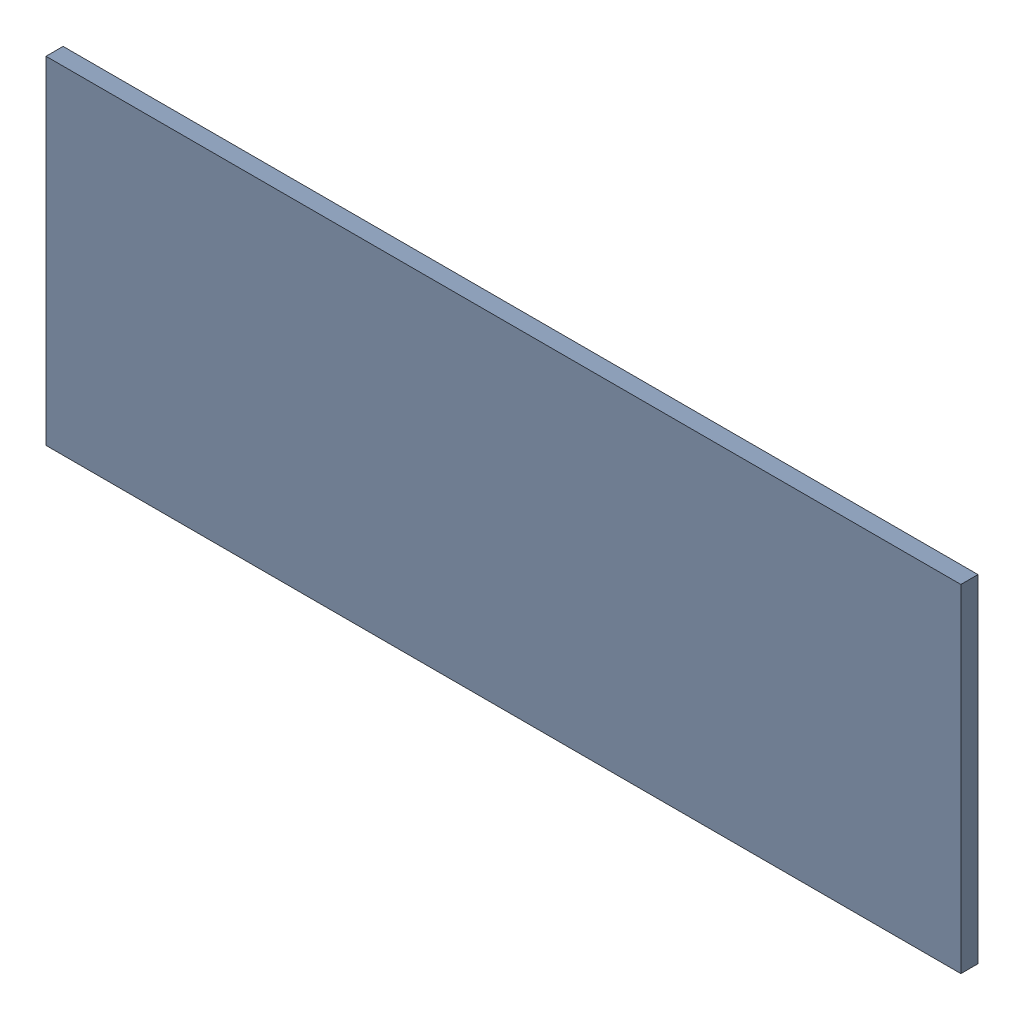
SolidWorks assembly Pad RAK4600-10(14.5mm,16.25mm) on Top Layer, configuration Predeterminado. Lengths in mm.
Overall size (1.9 0.7 0.04).
2 component instances, 1 part files, 0 mates.
Components (placement in the parent):
- Pad RAK4600-10(14.5mm,16.25mm) on Top Layer-1-1: Pad RAK4600-10(14.5mm,16.25mm) on Top Layer-1 [Predeterminado] at (-68.317 -44.187 -0.0457) size (1.9 0.7 0.04)
  - Pad RAK4600-10(14.5mm,16.25mm) on Top Layer-Part-1-1: Pad RAK4600-10(14.5mm,16.25mm) on Top Layer-Part-1 [Predeterminado] at origin size (1.9 0.7 0.04)
